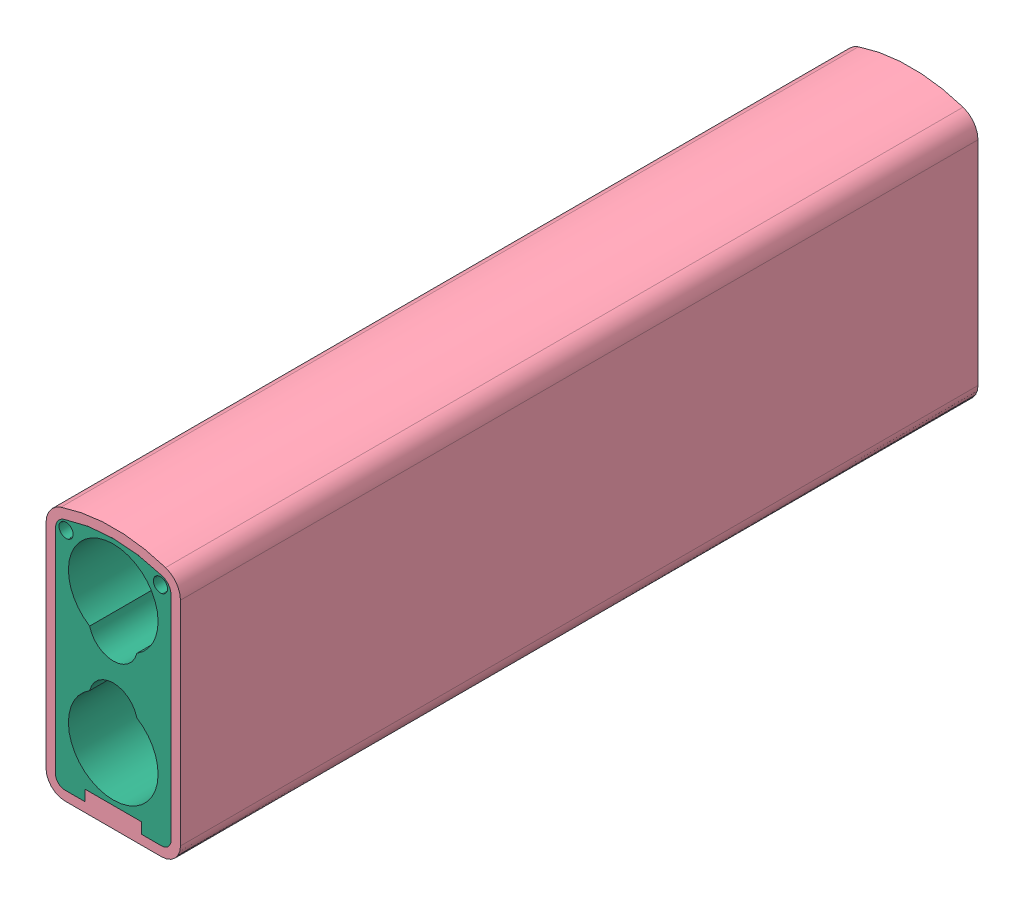
SolidWorks assembly Schulterstuetze, configuration Standard. Lengths in mm.
Overall size (28.5 55.3 169).
7 component instances, 6 part files, 17 mates.
Components (placement in the parent):
- Schulterstuetze Akku_Last-1: Schulterstuetze Akku_Last [Standard] at (-57.1984 -9.8358 -5) size (24.5 51.3 10)
- Schulterstuetze Akku_SecondLast-1: Schulterstuetze Akku_SecondLast [Standard] at (-57.1984 -9.8358 25) size (24.5 51.3 30)
- Schulterstuetze Akku-1: Schulterstuetze Akku [Standard] at (-57.1984 -9.8358 90) size (24.5 51.3 35)
- Schulterstütze Tube-1: Schulterstütze Tube [Standard] at (-32.6984 -9.8358 154) x (-1 0 0) z (0 0 -1) size (28.5 55.3 169)
- Schulterstuetze Akku-2: Schulterstuetze Akku [Standard] at (-57.1984 -9.8358 125) size (24.5 51.3 35)
- Schulterstuetze Akku_ThirdLast-2: Schulterstuetze Akku_ThirdLast [Standard] at (-57.1984 -9.8358 55) size (24.5 51.3 30)
- Schulterstuetze Akku_Short-1: Schulterstuetze Akku_Short [Standard] at (-57.1984 -9.8358 144) size (24.5 51.3 19)
Mates (geometry in assembly coordinates):
- Konzentrisch1: concentric aligned: cylinder of Schulterstuetze Akku_Last-1 through (-44.9484 28.6642 5) axis (0 0 -1) radius 9.5; cylinder of Schulterstuetze Akku_SecondLast-1 through (-44.9484 28.6642 35) axis (0 0 -1) radius 9.5
- Konzentrisch2: concentric aligned: cylinder of Schulterstuetze Akku_Last-1 through (-44.9484 0.6642 5) axis (0 0 -1) radius 9.5; cylinder of Schulterstuetze Akku_SecondLast-1 through (-44.9484 0.6642 35) axis (0 0 -1) radius 9.5
- Deckungsgleich1: coincident anti-aligned: plane of Schulterstuetze Akku_Last-1 through (-55.1984 -10.1358 5) normal (0 0 1); plane of Schulterstuetze Akku_SecondLast-1 through (-44.9484 4.0902 5) normal (0 0 -1)
- Deckungsgleich4: coincident anti-aligned: plane of Schulterstuetze Akku_Last-1 through (-57.1984 -10.1358 5) normal (-1 0 0); plane of Schulterstütze Tube-1 through (-57.1984 -10.1358 -15) normal (1 0 0)
- Deckungsgleich5: coincident anti-aligned: plane of Schulterstuetze Akku-1 through (-50.9484 -9.8358 100) normal (0 -1 0); plane of Schulterstütze Tube-1 through (-38.9484 -9.8358 -15) normal (0 1 0)
- Abstand1: distance = 10 mm aligned: plane of Schulterstuetze Akku_Last-1 through (-55.1984 -10.1358 -5) normal (0 0 -1); plane of Schulterstütze Tube-1 through (-34.6984 -10.1358 -15) normal (0 0 -1)
- Deckungsgleich7: coincident anti-aligned: plane of Schulterstuetze Akku-1 through (-55.1984 -10.1358 100) normal (0 0 1); plane of Schulterstuetze Akku-2 through (-44.9484 25.2383 100) normal (0 0 -1)
- Konzentrisch7: concentric aligned: cylinder of Schulterstuetze Akku-1 through (-44.9484 28.6642 100) axis (0 0 -1) radius 9.5; cylinder of Schulterstuetze Akku-2 through (-44.9484 28.6642 135) axis (0 0 -1) radius 9.5
- Konzentrisch8: concentric aligned: cylinder of Schulterstuetze Akku-1 through (-44.9484 0.6642 100) axis (0 0 -1) radius 9.5; cylinder of Schulterstuetze Akku-2 through (-44.9484 0.6642 135) axis (0 0 -1) radius 9.5
- Konzentrisch9: concentric aligned: cylinder of Schulterstuetze Akku_SecondLast-1 through (-44.9484 28.6642 35) axis (0 0 -1) radius 9.5; cylinder of Schulterstuetze Akku_ThirdLast-2 through (-44.9484 28.6642 65) axis (0 0 -1) radius 9.5
- Konzentrisch10: concentric aligned: cylinder of Schulterstuetze Akku_SecondLast-1 through (-44.9484 0.6642 35) axis (0 0 -1) radius 9.5; cylinder of Schulterstuetze Akku_ThirdLast-2 through (-44.9484 0.6642 65) axis (0 0 -1) radius 9.5
- Deckungsgleich8: coincident anti-aligned: plane of Schulterstuetze Akku_SecondLast-1 through (-55.1984 -10.1358 35) normal (0 0 1); plane of Schulterstuetze Akku_ThirdLast-2 through (-44.9484 25.2383 35) normal (0 0 -1)
- Deckungsgleich9: coincident anti-aligned: plane of Schulterstuetze Akku-1 through (-44.9484 25.2383 65) normal (0 0 -1); plane of Schulterstuetze Akku_ThirdLast-2 through (-55.1984 -10.1358 65) normal (0 0 1)
- Konzentrisch11: concentric aligned: cylinder of Schulterstuetze Akku-1 through (-44.9484 28.6642 100) axis (0 0 -1) radius 9.5; cylinder of Schulterstuetze Akku_ThirdLast-2 through (-44.9484 28.6642 65) axis (0 0 -1) radius 9.5
- Konzentrisch12: concentric: cylinder of Schulterstuetze Akku-2 through (-44.9484 28.6642 135) axis (0 0 -1) radius 9.5; cylinder of Schulterstuetze Akku_Short-1 through (-44.9484 28.6642 154) axis (0 0 -1) radius 9.5
- Konzentrisch13: concentric: cylinder of Schulterstuetze Akku-2 through (-44.9484 0.6642 135) axis (0 0 -1) radius 9.5; cylinder of Schulterstuetze Akku_Short-1 through (-44.9484 0.6642 154) axis (0 0 -1) radius 9.5
- Deckungsgleich10: coincident anti-aligned: plane of Schulterstuetze Akku-2 through (-55.1984 -10.1358 135) normal (0 0 1); plane of Schulterstuetze Akku_Short-1 through (-44.9484 4.0902 135) normal (0 0 -1)
